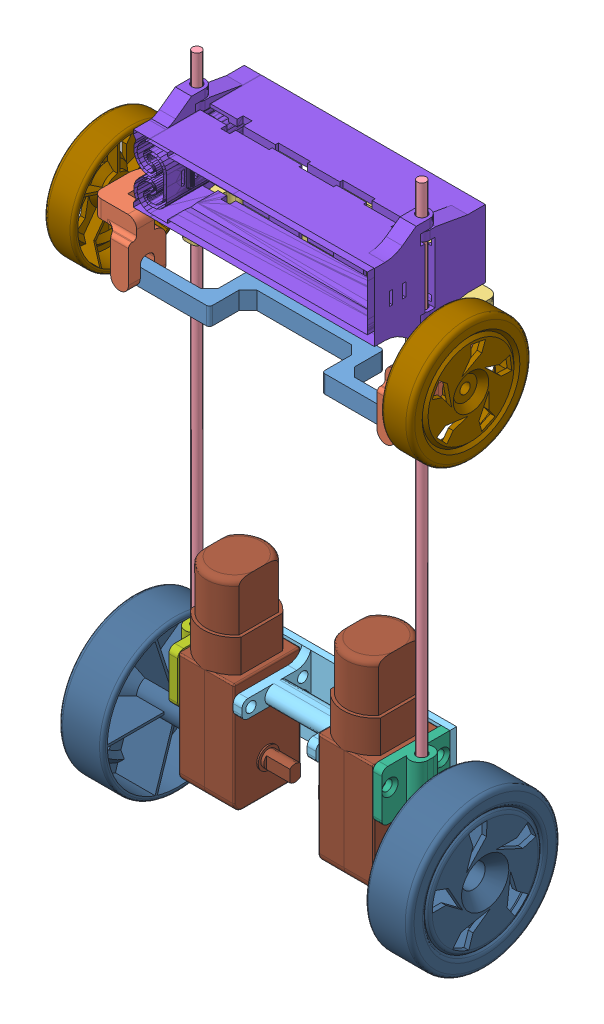
SolidWorks assembly Ensamblaje (sin Asientos), configuration Predeterminado. Lengths in mm.
Overall size (124 220.6 57.88).
21 component instances, 11 part files, 26 mates.
Components (placement in the parent):
- 15+11+16 (Direccion)-1: 15+11+16 (Direccion) [Predeterminado] at (-8.2347 -4.6293 32.0702) size (114 21 49.38)
  - 15-1: 15 [Predeterminado] at (-56.802 1.6746 98) size (98 6 26)
  - 16R-1: 16R [Predeterminado] at (-53.802 19.6746 97.62) x (-1 0 0) z (0 -1 0) size (15 24 21)
  - 16R-5: 16R [16L] at (30.198 19.6746 97.62) x (-1 0 0) z (0 -1 0) size (15 24 21)
  - 11R-8: 11R [Predeterminado] at (-46.802 11.6746 87.24) x (0 1 0) z (-1 0 0) size (11.54 34.26 47.5)
  - 11R-12: 11R [11L] at (-45.802 11.6746 87.24) x (0 1 0) z (-1 0 0) size (11.54 34.26 47.5)
- Palillo 180x3mm-1: Palillo 180x3mm [Predeterminado] at (-58.0366 58.5251 119.3102) x (1 0 0) z (0 -1 0) size (3 3 180)
- Palillo 180x3mm-2: Palillo 180x3mm [Predeterminado] at (17.9634 58.5251 119.3102) x (-0.109084 0 -0.994033) z (0 -1 0) size (3 3 180)
- Llantas Traseras-1: Llantas Traseras [Predeterminado] at (-17.364 -143.9749 119.2854) x (1 0 0) z (0 1 0) size (82 25.5 27.12)
  - 0-1: 0 [Predeterminado] at (-2.6726 -0.0247 28) size (72 25.5 27.12)
  - 1L-1: 1L [Predeterminado] at (35.3274 -0.0247 37.5) x (0 0 -1) z (1 0 0) size (27.12 23 8)
  - 1R-1: 1R [Predeterminado] at (-40.6726 -0.0247 37.5) x (0 0 -1) z (1 0 0) size (27.12 23 8)
- Portapilas-1: Portapilas [Predeterminado] at (4008.3145 -565.076 -82720.1237) size (81.5 33.48 37.48)
  - Portapila 18650-1: Portapila 18650 [Portapila B] at (-32851.1916 596.8515 73014.9) size (81.5 33.48 21.49)
  - Portapila 18650-2: Portapila 18650 [Predeterminado] at (-32934.0303 596.8612 92551.9559) x (1 0 0) z (0 0 -1) size (81.5 26.68 21.49)
- 12R-1: 12R [Predeterminado] at (-72.0366 12.0453 126.6902) x (0 0 1) z (-1 0 0) size (41 41 10)
- 13R-1: 13R [Predeterminado] at (-64.4366 -136.5749 119.3102) x (0 -1 0) z (-1 0 0) size (51 51 23)
- 12R-2: 12R [Predeterminado] at (31.9634 12.0453 126.6902) x (0 -0.000038 1) z (1 0 0) size (41 41 10)
- 13R-2: 13R [Predeterminado] at (24.3634 -136.5749 119.3102) x (0 -1 0) z (1 0 0) size (51 51 23)
- motor-1: motor [Default] at (12.9634 -136.5749 119.3102) x (0 0 -1) z (-1 0 0) size (22.6 65.53 37.6)
- motor-2: motor [Default] at (-34.2366 -136.5749 119.3102) x (0 0 -1) z (-1 0 0) size (22.6 65.53 37.6)
Mates (geometry in assembly coordinates):
- Concéntrica1: concentric: circle of assembly; circle of assembly; circle of 15+11+16 (Direccion)-1/11R-12; circle of Palillo 180x3mm-2
- Concéntrica2: concentric: circle of assembly; circle of assembly; circle of 15+11+16 (Direccion)-1/11R-8; circle of Palillo 180x3mm-1
- Coincidente1: coincident: plane of assembly; plane of assembly; plane of Palillo 180x3mm-1 through (-58.0366 58.5251 119.3102) normal (0 1 0); plane of Palillo 180x3mm-2 through (17.9634 58.5251 119.3102) normal (0 1 0)
- Concéntrica3: concentric: circle of assembly; circle of assembly; circle of Palillo 180x3mm-2; circle of Llantas Traseras-1/1L-1
- Concéntrica4: concentric: circle of assembly; circle of assembly; circle of Palillo 180x3mm-1; circle of Llantas Traseras-1/1R-1
- Coincidente3: coincident: plane of assembly; plane of assembly; plane of Palillo 180x3mm-1 through (-58.0366 -121.4749 119.3102) normal (0 -1 0); plane of Llantas Traseras-1/1R-1 through (-58.0366 -121.4749 119.3102) normal (0 1 0)
- Concéntrica5: concentric: circle of assembly; circle of assembly; circle of Palillo 180x3mm-2; circle of Portapilas-1/Portapila 18650-1
- Concéntrica6: concentric: circle of assembly; circle of assembly; circle of Palillo 180x3mm-1; circle of Portapilas-1/Portapila 18650-1
- Distancia1: distance = 10 mm: plane of assembly; plane of assembly; plane of Palillo 180x3mm-2 through (17.9634 58.5251 119.3102) normal (0 1 0); plane of Portapilas-1/Portapila 18650-1 through (-49.1741 48.5251 118.8201) normal (0 1 0)
- Distancia límite1: limit distance = 0 mm: plane of assembly; plane of assembly; plane of Portapilas-1/Portapila 18650-1 through (-49.1741 15.0453 118.8201) normal (0 -1 0); plane of 15+11+16 (Direccion)-1/11R-12 through (20.9634 15.0453 110.9961) normal (0 1 0)
- Concéntrica7: concentric: circle of assembly; circle of assembly; circle of 15+11+16 (Direccion)-1/16R-1; circle of 12R-1
- Concéntrica8: concentric: circle of assembly; circle of assembly; circle of 15+11+16 (Direccion)-1/16R-5; circle of 12R-2
- Coincidente5: coincident: plane of assembly; plane of assembly; plane of 15+11+16 (Direccion)-1/16R-1 through (-77.0366 9.0453 129.6902) normal (-1 0 0); plane of 12R-1 through (-77.0366 12.0453 126.6902) normal (1 0 0)
- Coincidente6: coincident: plane of assembly; plane of assembly; plane of 15+11+16 (Direccion)-1/16R-5 through (36.9634 9.0453 129.6902) normal (1 0 0); plane of 12R-2 through (36.9634 12.0453 126.6902) normal (-1 0 0)
- Concéntrica10: concentric: circle of assembly; circle of assembly; circle of Llantas Traseras-1/1L-1; circle of motor-1
- Concéntrica11: concentric: circle of assembly; circle of assembly; circle of Llantas Traseras-1/1L-1; circle of motor-1
- Concéntrica12: concentric: circle of assembly; circle of assembly; circle of Llantas Traseras-1/1R-1; circle of motor-2
- Concéntrica13: concentric: circle of assembly; circle of assembly; circle of Llantas Traseras-1/1R-1; circle of motor-2
- Coincidente7: coincident: plane of assembly; plane of assembly; plane of Llantas Traseras-1/1R-1 through (-53.0366 -125.4749 119.3102) normal (1 0 0); plane of motor-2 through (-53.0366 -136.5749 119.3102) normal (-1 0 0)
- Coincidente8: coincident: plane of assembly; plane of assembly; plane of Llantas Traseras-1/1L-1 through (12.9634 -125.4749 119.3102) normal (-1 0 0); plane of motor-1 through (12.9634 -136.5749 119.3102) normal (1 0 0)
- Concéntrica14: concentric: circle of assembly; circle of assembly; circle of 13R-2; circle of motor-1
- Paralelo2: parallel: line of assembly; line of assembly; line of 13R-2 through (16.3634 -134.5905 117.0602) axis (0 -1 0); line of motor-1 through (22.3634 -134.5624 117.5102) axis (0 -1 0)
- Coincidente11: coincident: plane of assembly; plane of assembly; plane of 13R-2 through (22.3634 -136.5749 119.3102) normal (-1 0 0); plane of motor-1 through (22.3634 -136.5749 119.3102) normal (1 0 0)
- Paralelo3: parallel: line of assembly; line of assembly; line of 13R-1 through (-56.4366 -138.5592 117.0602) axis (0 1 0); line of motor-2 through (-62.4366 -134.5624 117.5102) axis (0 -1 0)
- Concéntrica16: concentric: circle of assembly; circle of assembly; circle of 13R-1; circle of motor-2
- Coincidente13: coincident: plane of assembly; plane of assembly; plane of 13R-1 through (-62.4366 -136.5749 119.3102) normal (1 0 0); plane of motor-2 through (-62.4366 -136.5749 119.3102) normal (-1 0 0)
